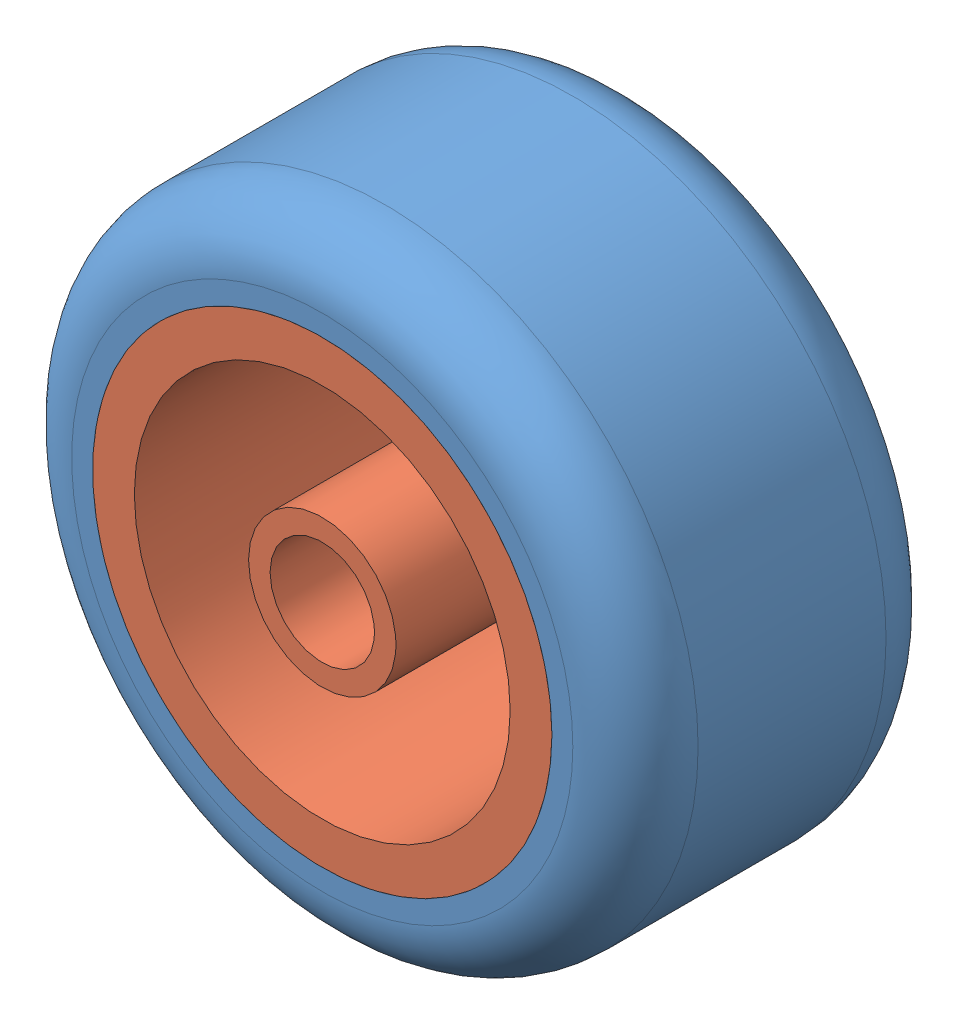
SolidWorks assembly AtulyaCompleteWheel, configuration Default. Lengths in mm.
Overall size (76.2 76.2 38.1).
2 component instances, 2 part files, 2 mates.
Components (placement in the parent):
- AtulyaTyre-1: AtulyaTyre [Default] at (7.3358 39.6521 69.7052) size (76.2 76.2 38.1)
- AtulyaWheelRim-1: AtulyaWheelRim [Default] at (-8.0982 67.2966 79.857) x (0 0 -1) z (1 0 0) size (35.56 55.88 55.88)
Mates (geometry in assembly coordinates):
- Concentric1: concentric: cylinder of AtulyaTyre-1 through (-8.0982 48.7112 107.8052) axis (0 0 -1) radius 33.02; cylinder of AtulyaWheelRim-1 through (-8.0982 48.7112 90.0252) axis (0 0 1) radius 25.4
- Coincident1: coincident aligned: circle of AtulyaTyre-1; plane of AtulyaWheelRim-1 through (-8.0982 71.5712 107.8052) normal (0 0 1)
